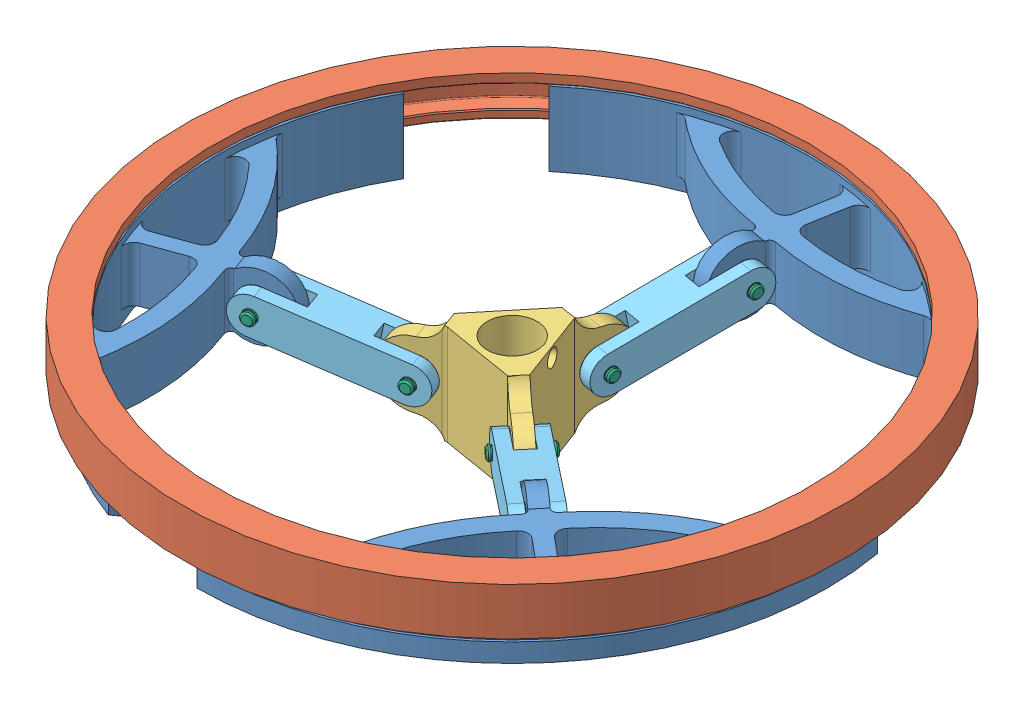
SolidWorks assembly Upper_Ring_Carriage_Clamps, configuration Default. Lengths in mm.
Overall size (196.47 29.88 195.11).
20 component instances, 6 part files, 16 mates.
Components (placement in the parent):
- Clamp_Ring_Concept-1: Clamp_Ring_Concept [Default] at (-27.5623 8.2477 38.9578) size (92.15 21.41 97.73)
- Ring_Concept-1: Ring_Concept [Default] at (-27.5623 8.3392 38.9578) size (167.64 21.41 167.64)
- Clamp_Ring_Concept-2: Clamp_Ring_Concept [Default] at (45.0279 8.2477 -86.7722) x (-0.5 0 -0.866025) z (0.866025 0 -0.5) size (92.15 21.41 97.73)
- Clamp_Ring_Concept-3: Clamp_Ring_Concept [Default] at (-100.1526 8.2477 -86.7722) x (-0.5 0 0.866025) z (-0.866025 0 -0.5) size (92.15 21.41 97.73)
- Carriage-1: Carriage [Default] at (-27.5623 -9.5323 -44.8622) x (0.936847 0 -0.349739) z (0.349739 0 0.936847) size (41.67 25.4 47.99)
- Bearing_RMA-1: Bearing_RMA [2342K61] at (-74.0304 8.8117 -27.7924) x (0.939693 0 -0.34202) z (0.34202 0 0.939693) size (9.53 9.53 3.97)
- Linkage-2: Linkage [Default] at (0.06 0 -0.0715) size (38.12 15.04 34.41)
- Bearing_RMA-2: Bearing_RMA [2342K61] at (10.4545 8.8117 -13.1545) x (-0.766044 0 -0.642788) z (0.642788 0 -0.766044) size (9.53 9.53 3.97)
- Bearing_RMA-3: Bearing_RMA [2342K61] at (-19.1111 8.8117 -93.6395) x (-0.173648 0 0.984808) z (-0.984808 0 -0.173648) size (9.53 9.53 3.97)
- Bearing_RMA-4: Bearing_RMA [2342K61] at (-44.5111 3.1677 -38.5376) x (0.939693 0 -0.34202) z (0.34202 0 0.939693) size (9.53 9.53 3.97)
- Bearing_RMA-5: Bearing_RMA [2342K61] at (-13.6107 3.1677 -33.3464) x (-0.766044 0 -0.642788) z (0.642788 0 -0.766044) size (9.53 9.53 3.97)
- Bearing_RMA-6: Bearing_RMA [2342K61] at (-24.5651 3.1677 -62.7025) x (-0.173648 0 0.984808) z (-0.984808 0 -0.173648) size (9.53 9.53 3.97)
- Linkage-3: Linkage [Default] at (-2.5836 0 -91.1791) x (-0.5 0 -0.866025) z (0.866025 0 -0.5) size (38.12 15.04 34.41)
- Linkage-4: Linkage [Default] at (-80.1633 0 -43.3359) x (-0.5 0 0.866025) z (-0.866025 0 -0.5) size (38.12 15.04 34.41)
- Dowell_Pin_1-1: Dowell_Pin_1 [Default] at (-19.1831 8.8117 -93.6522) x (0.030154 0.984808 -0.17101) z (-0.17101 0.173648 0.969846) size (3.17 13.21 3.17)
- Dowell_Pin_1-2: Dowell_Pin_1 [Default] at (-24.6381 3.1677 -62.7154) x (0.030154 0.984808 -0.17101) z (-0.17101 0.173648 0.969846) size (3.17 13.21 3.17)
- Dowell_Pin_1-3: Dowell_Pin_1 [Default] at (-44.4858 3.1677 -38.468) x (-0.163176 0.984808 0.059391) z (0.925417 0.173648 -0.336824) size (3.17 13.21 3.17)
- Dowell_Pin_1-4: Dowell_Pin_1 [Default] at (-13.5631 3.1677 -33.4031) x (0.133022 0.984808 0.111619) z (-0.754407 0.173648 -0.633022) size (3.17 13.21 3.17)
- Dowell_Pin_1-5: Dowell_Pin_1 [Default] at (-74.0054 8.8117 -27.7238) x (-0.163176 0.984808 0.059391) z (0.925417 0.173648 -0.336824) size (3.17 13.21 3.17)
- Dowell_Pin_1-6: Dowell_Pin_1 [Default] at (10.5015 8.8117 -13.2105) x (0.133022 0.984808 0.111619) z (-0.754407 0.173648 -0.633022) size (3.17 13.21 3.17)
Mates (geometry in assembly coordinates):
- Parallel1: parallel: cylinder of Clamp_Ring_Concept-1 through (-27.5623 14.2526 -44.8622) axis (0 -1 0) radius 80.1166; cylinder of Ring_Concept-1 through (-27.5623 14.3441 -44.8622) axis (0 -1 0) radius 80.82
- Coincident4: coincident: plane of Clamp_Ring_Concept-2 through (-35.3289 15.8677 -109.4262) normal (0 1 0); plane of Carriage-1 through (-27.5623 15.8677 -44.8622) normal (0 1 0)
- Concentric12: concentric: cylinder of Clamp_Ring_Concept-3 through (-73.3517 8.8117 -25.9277) axis (-0.34202 0 -0.939693) radius 4.699; cylinder of Bearing_RMA-1 through (-73.3517 8.8117 -25.9277) axis (0.34202 0 0.939693) radius 4.7625
- Coincident5: coincident: plane of Clamp_Ring_Concept-3 through (-74.2561 1.8977 -25.5985) normal (0.34202 0 0.939693); plane of Bearing_RMA-1 through (-73.3517 13.3758 -25.9277) normal (0.34202 0 0.939693)
- Concentric13: concentric: cylinder of Carriage-1 through (-45.2224 3.1677 -40.4918) axis (0.34202 0 0.939693) radius 4.6355; cylinder of Bearing_RMA-4 through (-43.8324 3.1677 -36.6729) axis (0.34202 0 0.939693) radius 4.7625
- Coincident6: coincident: plane of Carriage-1 through (-44.0969 17.957 -36.5767) normal (0.34202 0 0.939693); plane of Bearing_RMA-4 through (-43.8324 7.7318 -36.6729) normal (0.34202 0 0.939693)
- Concentric14: concentric: cylinder of Linkage-2 through (13.8485 8.8117 -17.1993) axis (-0.642788 0 0.766044) radius 1.651; cylinder of Bearing_RMA-2 through (11.7301 8.8117 -14.6747) axis (0.642788 0 -0.766044) radius 1.5875
- Parallel4: parallel: plane of Linkage-2 through (13.3492 4.0177 -7.8369) normal (0.642788 0 -0.766044); plane of Bearing_RMA-2 through (9.179 10.5977 -11.6344) normal (-0.642788 0 0.766044)
- Parallel6: parallel: plane of Clamp_Ring_Concept-1 through (12.4674 1.8977 -14.056) normal (0.642788 0 -0.766044); plane of Linkage-2 through (16.1247 4.0177 -11.1446) normal (-0.642788 0 0.766044)
- Concentric15: concentric: cylinder of Linkage-2 through (-10.2161 3.1677 -37.3919) axis (-0.642788 0 0.766044) radius 1.651; cylinder of Bearing_RMA-5 through (-12.3352 3.1677 -34.8665) axis (0.642788 0 -0.766044) radius 1.5875
- Concentric16: concentric: cylinder of Bearing_RMA-3 through (-21.0654 8.8117 -93.9841) axis (-0.984808 0 -0.173648) radius 1.5875; cylinder of Dowell_Pin_1-1 through (-19.1831 8.8117 -93.6522) axis (0.984808 0 0.173648) radius 1.5875
- Coincident11: coincident: plane of Linkage-3 through (-29.766 3.1677 -63.6196) normal (-0.984808 0 -0.173648); plane of Dowell_Pin_1-1 through (-24.3588 7.2484 -94.2849) normal (-0.984808 0 -0.173648)
- Concentric17: concentric: cylinder of Bearing_RMA-6 through (-26.5194 3.1677 -63.0471) axis (-0.984808 0 -0.173648) radius 1.5875; cylinder of Dowell_Pin_1-2 through (-24.6381 3.1677 -62.7154) axis (0.984808 0 0.173648) radius 1.5875
- Coincident12: coincident: plane of Linkage-3 through (-29.766 3.1677 -63.6196) normal (-0.984808 0 -0.173648); plane of Dowell_Pin_1-2 through (-29.8138 1.6043 -63.3481) normal (-0.984808 0 -0.173648)
- Parallel7: parallel: plane of Clamp_Ring_Concept-3 through (-74.2561 1.8977 -25.5985) normal (0.34202 0 0.939693); plane of Linkage-4 through (-78.6061 4.0177 -23.8869) normal (-0.34202 0 -0.939693)
- Parallel8: parallel: plane of Clamp_Ring_Concept-3 through (-75.6461 1.8977 -29.4174) normal (-0.34202 0 -0.939693); plane of Linkage-4 through (-80.0829 4.0177 -27.9444) normal (0.34202 0 0.939693)
